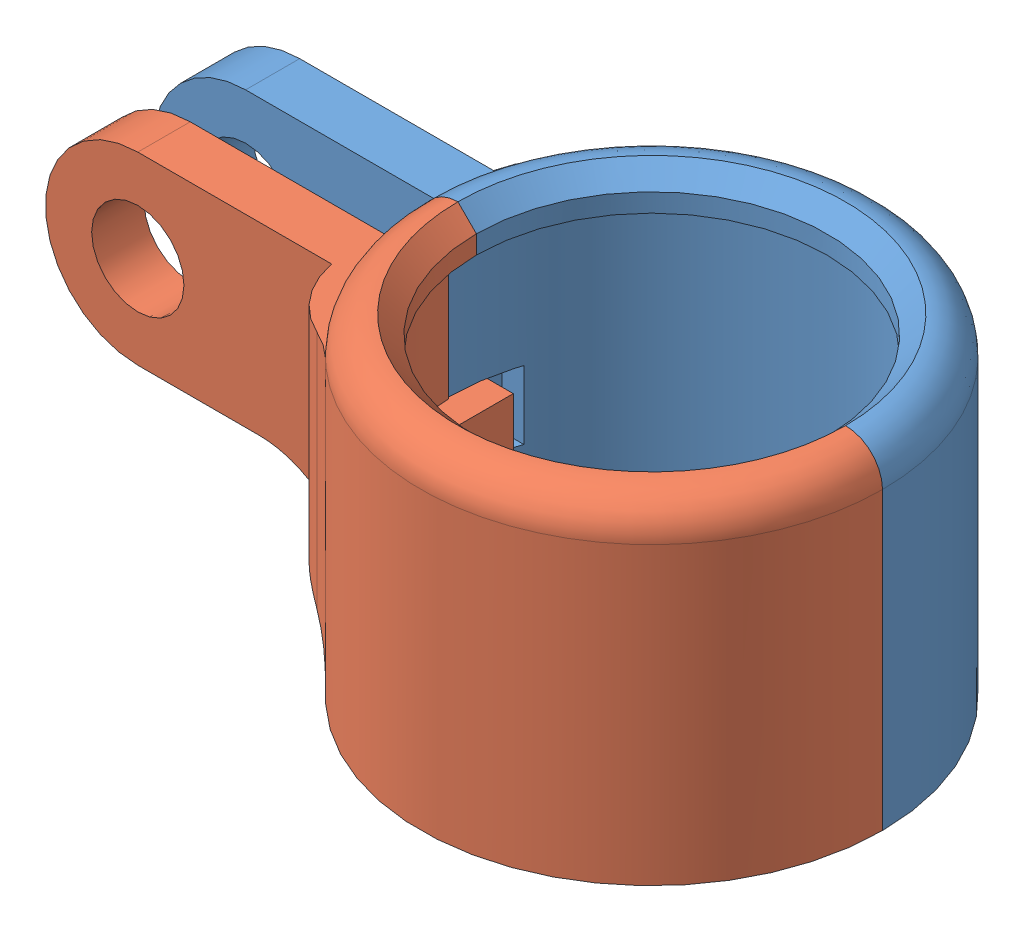
SolidWorks assembly mini_lamp, configuration Défaut. Lengths in mm.
Overall size (41 18 25).
2 component instances, 2 part files, 4 mates.
Components (placement in the parent):
- Mini_Lamp_Support_right-1: Mini_Lamp_Support_right [Défaut] at (-112.4637 20.0365 5.25) size (41 18 14.5)
- Mini_Lamp_Support_left-1: Mini_Lamp_Support_left [Défaut] at (-112.4637 20.0365 5.25) x (-1 0 0) z (0 0 -1) size (41 18 14.5)
Mates (geometry in assembly coordinates):
- Coïncidente1: coincident: plane of Mini_Lamp_Support_right-1 through (-112.4637 20.0365 5.25) normal (0 0 1); plane of Mini_Lamp_Support_left-1 through (-112.4637 -29.9683 5.25) normal (0 0 -1)
- Parallèle1: parallel: plane of Mini_Lamp_Support_right-1 through (-112.4637 20.0365 5.25) normal (0 -1 0); plane of Mini_Lamp_Support_left-1 through (-112.4637 -29.9683 5.25) normal (0 -1 0)
- Coïncidente4: coincident: line of Mini_Lamp_Support_right-1 through (-124.9637 20.0365 5.25) axis (0 1 0); line of Mini_Lamp_Support_left-1 through (-124.9637 -29.9683 5.25) axis (0 1 0)
- Coïncidente5: coincident aligned: plane of Mini_Lamp_Support_right-1 through (-112.4637 20.0365 5.25) normal (0 -1 0); plane of Mini_Lamp_Support_left-1 through (-112.4637 20.0365 5.25) normal (0 -1 0)
